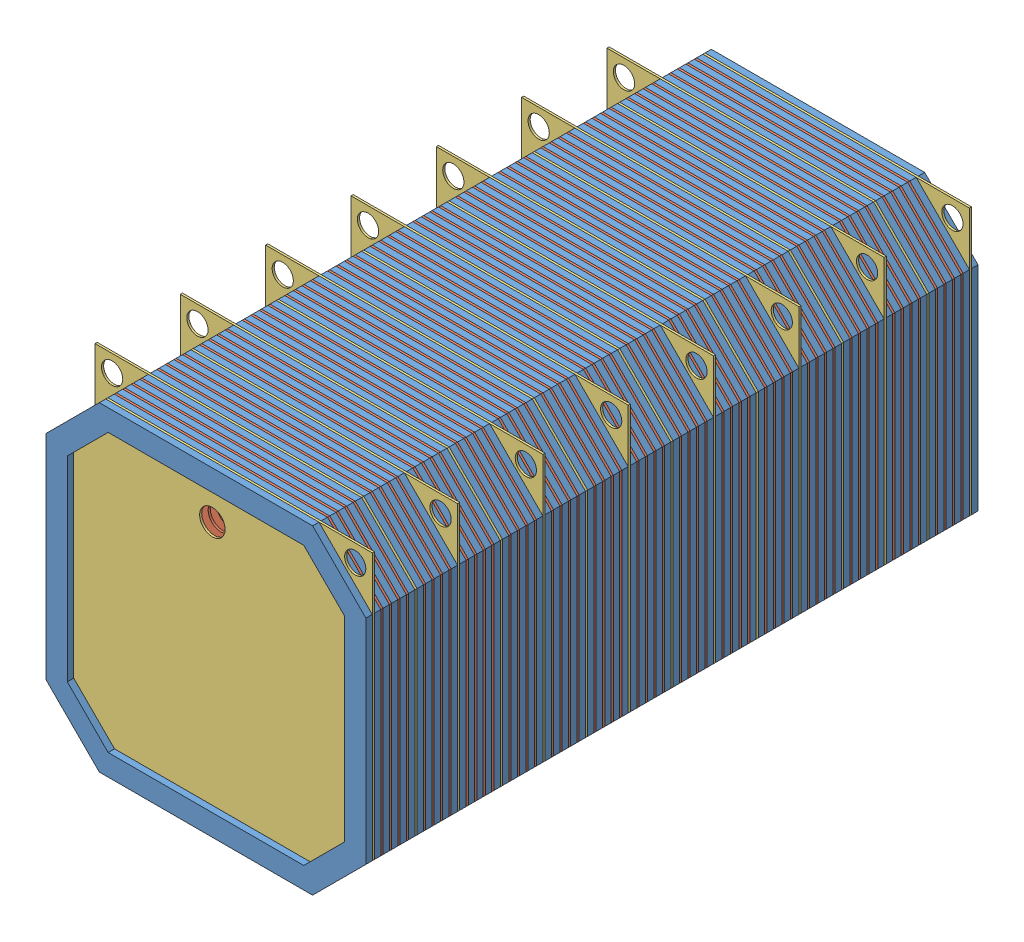
SolidWorks assembly All Battery Block, configuration Default. Lengths in mm.
Overall size (150 150 287).
150 component instances, 3 part files, 11 mates.
Components (placement in the parent):
- Block Battery-1: Block Battery [Default] at (-175.922 -206.6429 -286.6039) size (150 150 40)
  - Gasket-12: Gasket [Default] at (244.3004 275.7985 390.286) size (150 150 3)
  - Plate-1-7: Plate-1 [Default] at (239.8004 279.4658 389.286) size (150 150 1)
  - Gasket-13: Gasket [Default] at (244.3004 275.7985 386.286) size (150 150 3)
  - Plate-1-8: Plate-1 [Default] at (239.8004 279.4658 385.286) size (150 150 1)
  - Gasket-14: Gasket [Default] at (244.3004 275.7985 382.286) size (150 150 3)
  - Plate-2-4: Plate-2 [Default] at (239.8004 279.4658 381.286) size (150 150 1)
  - Plate-1-10: Plate-1 [Default] at (239.8004 279.4658 393.286) size (150 150 1)
  - Gasket-16: Gasket [Default] at (244.3004 275.7985 394.286) size (150 150 3)
  - Plate-1-11: Plate-1 [Default] at (239.8004 279.4658 397.286) size (150 150 1)
  - Gasket-17: Gasket [Default] at (244.3004 275.7985 398.286) size (150 150 3)
  - Plate-2-5: Plate-2 [Default] at (239.8004 279.4658 402.286) x (-1 0 0) z (0 0 -1) size (150 150 1)
  - Gasket-18: Gasket [Default] at (244.3004 275.7985 402.286) size (150 150 3)
  - Plate-1-12: Plate-1 [Default] at (239.8004 279.4658 405.286) size (150 150 1)
  - Gasket-19: Gasket [Default] at (244.3004 275.7985 406.286) size (150 150 3)
  - Plate-1-13: Plate-1 [Default] at (239.8004 279.4658 409.286) size (150 150 1)
  - Gasket-20: Gasket [Default] at (244.3004 275.7985 410.286) size (150 150 3)
  - Plate-1-14: Plate-1 [Default] at (239.8004 279.4658 413.286) size (150 150 1)
  - Gasket-21: Gasket [Default] at (244.3004 275.7985 414.286) size (150 150 3)
  - Plate-1-15: Plate-1 [Default] at (239.8004 279.4658 417.286) size (150 150 1)
  - Gasket-22: Gasket [Default] at (244.3004 275.7985 418.286) size (150 150 3)
- Block Battery-2: Block Battery [Default] at (-175.922 -206.6429 -246.6039) size (150 150 40)
  - Gasket-12: Gasket [Default] at (244.3004 275.7985 390.286) size (150 150 3)
  - Plate-1-7: Plate-1 [Default] at (239.8004 279.4658 389.286) size (150 150 1)
  - Gasket-13: Gasket [Default] at (244.3004 275.7985 386.286) size (150 150 3)
  - Plate-1-8: Plate-1 [Default] at (239.8004 279.4658 385.286) size (150 150 1)
  - Gasket-14: Gasket [Default] at (244.3004 275.7985 382.286) size (150 150 3)
  - Plate-2-4: Plate-2 [Default] at (239.8004 279.4658 381.286) size (150 150 1)
  - Plate-1-10: Plate-1 [Default] at (239.8004 279.4658 393.286) size (150 150 1)
  - Gasket-16: Gasket [Default] at (244.3004 275.7985 394.286) size (150 150 3)
  - Plate-1-11: Plate-1 [Default] at (239.8004 279.4658 397.286) size (150 150 1)
  - Gasket-17: Gasket [Default] at (244.3004 275.7985 398.286) size (150 150 3)
  - Plate-2-5: Plate-2 [Default] at (239.8004 279.4658 402.286) x (-1 0 0) z (0 0 -1) size (150 150 1)
  - Gasket-18: Gasket [Default] at (244.3004 275.7985 402.286) size (150 150 3)
  - Plate-1-12: Plate-1 [Default] at (239.8004 279.4658 405.286) size (150 150 1)
  - Gasket-19: Gasket [Default] at (244.3004 275.7985 406.286) size (150 150 3)
  - Plate-1-13: Plate-1 [Default] at (239.8004 279.4658 409.286) size (150 150 1)
  - Gasket-20: Gasket [Default] at (244.3004 275.7985 410.286) size (150 150 3)
  - Plate-1-14: Plate-1 [Default] at (239.8004 279.4658 413.286) size (150 150 1)
  - Gasket-21: Gasket [Default] at (244.3004 275.7985 414.286) size (150 150 3)
  - Plate-1-15: Plate-1 [Default] at (239.8004 279.4658 417.286) size (150 150 1)
  - Gasket-22: Gasket [Default] at (244.3004 275.7985 418.286) size (150 150 3)
- Block Battery-3: Block Battery [Default] at (-175.922 -206.6429 -206.6039) size (150 150 40)
  - Gasket-12: Gasket [Default] at (244.3004 275.7985 390.286) size (150 150 3)
  - Plate-1-7: Plate-1 [Default] at (239.8004 279.4658 389.286) size (150 150 1)
  - Gasket-13: Gasket [Default] at (244.3004 275.7985 386.286) size (150 150 3)
  - Plate-1-8: Plate-1 [Default] at (239.8004 279.4658 385.286) size (150 150 1)
  - Gasket-14: Gasket [Default] at (244.3004 275.7985 382.286) size (150 150 3)
  - Plate-2-4: Plate-2 [Default] at (239.8004 279.4658 381.286) size (150 150 1)
  - Plate-1-10: Plate-1 [Default] at (239.8004 279.4658 393.286) size (150 150 1)
  - Gasket-16: Gasket [Default] at (244.3004 275.7985 394.286) size (150 150 3)
  - Plate-1-11: Plate-1 [Default] at (239.8004 279.4658 397.286) size (150 150 1)
  - Gasket-17: Gasket [Default] at (244.3004 275.7985 398.286) size (150 150 3)
  - Plate-2-5: Plate-2 [Default] at (239.8004 279.4658 402.286) x (-1 0 0) z (0 0 -1) size (150 150 1)
  - Gasket-18: Gasket [Default] at (244.3004 275.7985 402.286) size (150 150 3)
  - Plate-1-12: Plate-1 [Default] at (239.8004 279.4658 405.286) size (150 150 1)
  - Gasket-19: Gasket [Default] at (244.3004 275.7985 406.286) size (150 150 3)
  - Plate-1-13: Plate-1 [Default] at (239.8004 279.4658 409.286) size (150 150 1)
  - Gasket-20: Gasket [Default] at (244.3004 275.7985 410.286) size (150 150 3)
  - Plate-1-14: Plate-1 [Default] at (239.8004 279.4658 413.286) size (150 150 1)
  - Gasket-21: Gasket [Default] at (244.3004 275.7985 414.286) size (150 150 3)
  - Plate-1-15: Plate-1 [Default] at (239.8004 279.4658 417.286) size (150 150 1)
  - Gasket-22: Gasket [Default] at (244.3004 275.7985 418.286) size (150 150 3)
- Block Battery-4: Block Battery [Default] at (-175.922 -206.6429 -166.6039) size (150 150 40)
  - Gasket-12: Gasket [Default] at (244.3004 275.7985 390.286) size (150 150 3)
  - Plate-1-7: Plate-1 [Default] at (239.8004 279.4658 389.286) size (150 150 1)
  - Gasket-13: Gasket [Default] at (244.3004 275.7985 386.286) size (150 150 3)
  - Plate-1-8: Plate-1 [Default] at (239.8004 279.4658 385.286) size (150 150 1)
  - Gasket-14: Gasket [Default] at (244.3004 275.7985 382.286) size (150 150 3)
  - Plate-2-4: Plate-2 [Default] at (239.8004 279.4658 381.286) size (150 150 1)
  - Plate-1-10: Plate-1 [Default] at (239.8004 279.4658 393.286) size (150 150 1)
  - Gasket-16: Gasket [Default] at (244.3004 275.7985 394.286) size (150 150 3)
  - Plate-1-11: Plate-1 [Default] at (239.8004 279.4658 397.286) size (150 150 1)
  - Gasket-17: Gasket [Default] at (244.3004 275.7985 398.286) size (150 150 3)
  - Plate-2-5: Plate-2 [Default] at (239.8004 279.4658 402.286) x (-1 0 0) z (0 0 -1) size (150 150 1)
  - Gasket-18: Gasket [Default] at (244.3004 275.7985 402.286) size (150 150 3)
  - Plate-1-12: Plate-1 [Default] at (239.8004 279.4658 405.286) size (150 150 1)
  - Gasket-19: Gasket [Default] at (244.3004 275.7985 406.286) size (150 150 3)
  - Plate-1-13: Plate-1 [Default] at (239.8004 279.4658 409.286) size (150 150 1)
  - Gasket-20: Gasket [Default] at (244.3004 275.7985 410.286) size (150 150 3)
  - Plate-1-14: Plate-1 [Default] at (239.8004 279.4658 413.286) size (150 150 1)
  - Gasket-21: Gasket [Default] at (244.3004 275.7985 414.286) size (150 150 3)
  - Plate-1-15: Plate-1 [Default] at (239.8004 279.4658 417.286) size (150 150 1)
  - Gasket-22: Gasket [Default] at (244.3004 275.7985 418.286) size (150 150 3)
- Block Battery-5: Block Battery [Default] at (-175.922 -206.6429 -126.6039) size (150 150 40)
  - Gasket-12: Gasket [Default] at (244.3004 275.7985 390.286) size (150 150 3)
  - Plate-1-7: Plate-1 [Default] at (239.8004 279.4658 389.286) size (150 150 1)
  - Gasket-13: Gasket [Default] at (244.3004 275.7985 386.286) size (150 150 3)
  - Plate-1-8: Plate-1 [Default] at (239.8004 279.4658 385.286) size (150 150 1)
  - Gasket-14: Gasket [Default] at (244.3004 275.7985 382.286) size (150 150 3)
  - Plate-2-4: Plate-2 [Default] at (239.8004 279.4658 381.286) size (150 150 1)
  - Plate-1-10: Plate-1 [Default] at (239.8004 279.4658 393.286) size (150 150 1)
  - Gasket-16: Gasket [Default] at (244.3004 275.7985 394.286) size (150 150 3)
  - Plate-1-11: Plate-1 [Default] at (239.8004 279.4658 397.286) size (150 150 1)
  - Gasket-17: Gasket [Default] at (244.3004 275.7985 398.286) size (150 150 3)
  - Plate-2-5: Plate-2 [Default] at (239.8004 279.4658 402.286) x (-1 0 0) z (0 0 -1) size (150 150 1)
  - Gasket-18: Gasket [Default] at (244.3004 275.7985 402.286) size (150 150 3)
  - Plate-1-12: Plate-1 [Default] at (239.8004 279.4658 405.286) size (150 150 1)
  - Gasket-19: Gasket [Default] at (244.3004 275.7985 406.286) size (150 150 3)
  - Plate-1-13: Plate-1 [Default] at (239.8004 279.4658 409.286) size (150 150 1)
  - Gasket-20: Gasket [Default] at (244.3004 275.7985 410.286) size (150 150 3)
  - Plate-1-14: Plate-1 [Default] at (239.8004 279.4658 413.286) size (150 150 1)
  - Gasket-21: Gasket [Default] at (244.3004 275.7985 414.286) size (150 150 3)
  - Plate-1-15: Plate-1 [Default] at (239.8004 279.4658 417.286) size (150 150 1)
  - Gasket-22: Gasket [Default] at (244.3004 275.7985 418.286) size (150 150 3)
- Block Battery-6: Block Battery [Default] at (-175.922 -206.6429 -86.6039) size (150 150 40)
  - Gasket-12: Gasket [Default] at (244.3004 275.7985 390.286) size (150 150 3)
  - Plate-1-7: Plate-1 [Default] at (239.8004 279.4658 389.286) size (150 150 1)
  - Gasket-13: Gasket [Default] at (244.3004 275.7985 386.286) size (150 150 3)
  - Plate-1-8: Plate-1 [Default] at (239.8004 279.4658 385.286) size (150 150 1)
  - Gasket-14: Gasket [Default] at (244.3004 275.7985 382.286) size (150 150 3)
  - Plate-2-4: Plate-2 [Default] at (239.8004 279.4658 381.286) size (150 150 1)
  - Plate-1-10: Plate-1 [Default] at (239.8004 279.4658 393.286) size (150 150 1)
  - Gasket-16: Gasket [Default] at (244.3004 275.7985 394.286) size (150 150 3)
  - Plate-1-11: Plate-1 [Default] at (239.8004 279.4658 397.286) size (150 150 1)
  - Gasket-17: Gasket [Default] at (244.3004 275.7985 398.286) size (150 150 3)
  - Plate-2-5: Plate-2 [Default] at (239.8004 279.4658 402.286) x (-1 0 0) z (0 0 -1) size (150 150 1)
  - Gasket-18: Gasket [Default] at (244.3004 275.7985 402.286) size (150 150 3)
  - Plate-1-12: Plate-1 [Default] at (239.8004 279.4658 405.286) size (150 150 1)
  - Gasket-19: Gasket [Default] at (244.3004 275.7985 406.286) size (150 150 3)
  - Plate-1-13: Plate-1 [Default] at (239.8004 279.4658 409.286) size (150 150 1)
  - Gasket-20: Gasket [Default] at (244.3004 275.7985 410.286) size (150 150 3)
  - Plate-1-14: Plate-1 [Default] at (239.8004 279.4658 413.286) size (150 150 1)
  - Gasket-21: Gasket [Default] at (244.3004 275.7985 414.286) size (150 150 3)
  - Plate-1-15: Plate-1 [Default] at (239.8004 279.4658 417.286) size (150 150 1)
  - Gasket-22: Gasket [Default] at (244.3004 275.7985 418.286) size (150 150 3)
- Block Battery-7: Block Battery [Default] at (-175.922 -206.6429 -46.6039) size (150 150 40)
  - Gasket-12: Gasket [Default] at (244.3004 275.7985 390.286) size (150 150 3)
  - Plate-1-7: Plate-1 [Default] at (239.8004 279.4658 389.286) size (150 150 1)
  - Gasket-13: Gasket [Default] at (244.3004 275.7985 386.286) size (150 150 3)
  - Plate-1-8: Plate-1 [Default] at (239.8004 279.4658 385.286) size (150 150 1)
  - Gasket-14: Gasket [Default] at (244.3004 275.7985 382.286) size (150 150 3)
  - Plate-2-4: Plate-2 [Default] at (239.8004 279.4658 381.286) size (150 150 1)
  - Plate-1-10: Plate-1 [Default] at (239.8004 279.4658 393.286) size (150 150 1)
  - Gasket-16: Gasket [Default] at (244.3004 275.7985 394.286) size (150 150 3)
  - Plate-1-11: Plate-1 [Default] at (239.8004 279.4658 397.286) size (150 150 1)
  - Gasket-17: Gasket [Default] at (244.3004 275.7985 398.286) size (150 150 3)
  - Plate-2-5: Plate-2 [Default] at (239.8004 279.4658 402.286) x (-1 0 0) z (0 0 -1) size (150 150 1)
  - Gasket-18: Gasket [Default] at (244.3004 275.7985 402.286) size (150 150 3)
  - Plate-1-12: Plate-1 [Default] at (239.8004 279.4658 405.286) size (150 150 1)
  - Gasket-19: Gasket [Default] at (244.3004 275.7985 406.286) size (150 150 3)
  - Plate-1-13: Plate-1 [Default] at (239.8004 279.4658 409.286) size (150 150 1)
  - Gasket-20: Gasket [Default] at (244.3004 275.7985 410.286) size (150 150 3)
  - Plate-1-14: Plate-1 [Default] at (239.8004 279.4658 413.286) size (150 150 1)
  - Gasket-21: Gasket [Default] at (244.3004 275.7985 414.286) size (150 150 3)
  - Plate-1-15: Plate-1 [Default] at (239.8004 279.4658 417.286) size (150 150 1)
  - Gasket-22: Gasket [Default] at (244.3004 275.7985 418.286) size (150 150 3)
- Plate-2-1: Plate-2 [Default] at (63.8784 72.8229 374.682) size (150 150 1)
- Gasket-1: Gasket [Default] at (68.3784 69.1556 375.682) size (150 150 3)
- Gasket-2: Gasket [Default] at (68.3784 69.1556 91.682) size (150 150 3)
Mates (geometry in assembly coordinates):
- Coincident1: coincident: point of Block Battery-1/Gasket-22; point of Block Battery-2/Plate-2-4
- Coincident2: coincident: point of Block Battery-2/Gasket-22; point of Block Battery-3/Plate-2-4
- Coincident3: coincident: point of Block Battery-3/Gasket-22; point of Block Battery-4/Plate-2-4
- Coincident4: coincident: point of Block Battery-4/Gasket-22; point of Block Battery-5/Plate-2-4
- Coincident5: coincident: point of Block Battery-5/Gasket-22; point of Block Battery-6/Plate-2-4
- Coincident6: coincident: point of Block Battery-6/Gasket-22; point of Block Battery-7/Plate-2-4
- Parallel1: parallel: plane of Block Battery-7/Plate-1-15 through (63.8784 72.8229 371.682) normal (0 0 1); plane of Plate-2-1 through (63.8784 72.8229 375.682) normal (0 0 1)
- Coincident8: coincident: point of Block Battery-7/Gasket-22; point of Plate-2-1
- Coincident9: coincident: point of Plate-2-1; point of Gasket-1
- Parallel2: parallel: plane of Block Battery-1/Plate-2-4 through (63.8784 72.8229 94.682) normal (0 0 -1); plane of Gasket-2 through (68.3784 69.1556 91.682) normal (0 0 -1)
- Coincident10: coincident: point of Block Battery-1/Plate-2-4; point of Gasket-2
